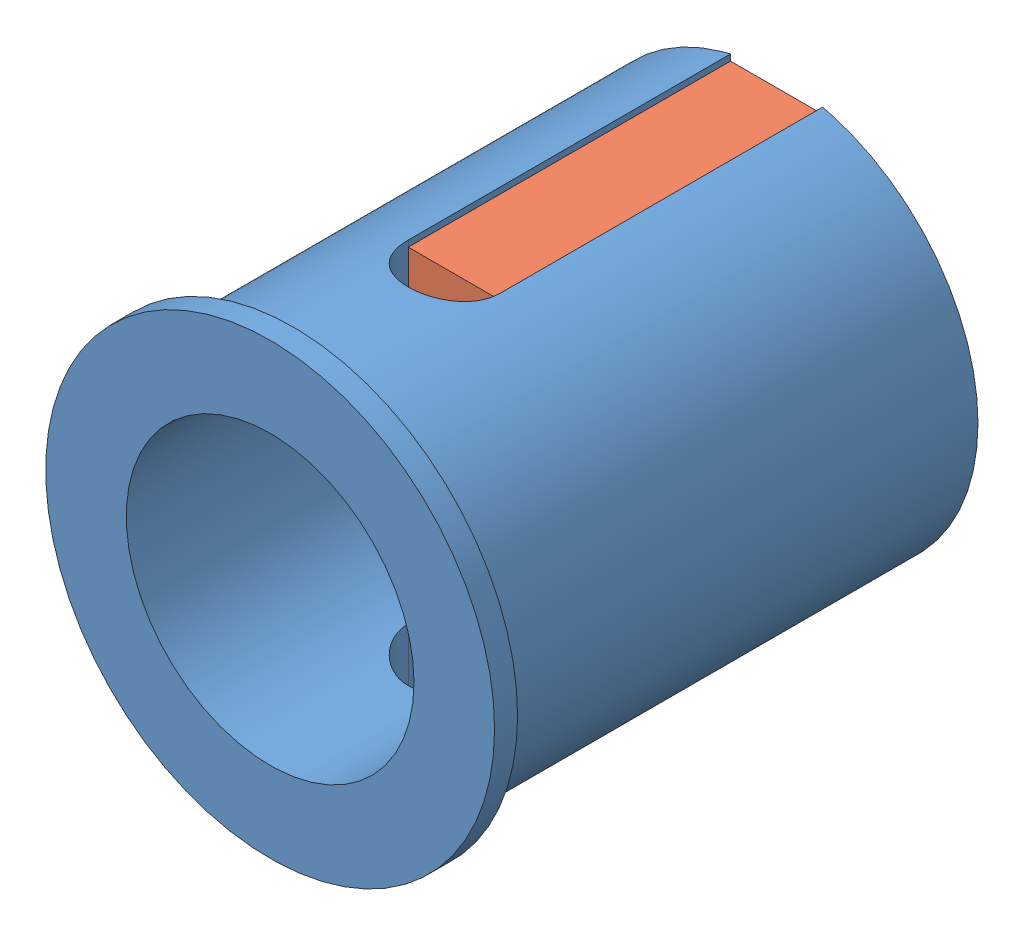
SolidWorks assembly ТП.002.08.01.02.00 - Втулка шкива, configuration 00. Lengths in mm.
Overall size (39 39 44).
2 component instances, 2 part files, 4 mates.
Components (placement in the parent):
- ТП.002.08.01.02.01 - Втулка шкива приводного-1: ТП.002.08.01.02.01 - Втулка шкива приводного [--] at origin size (39 39 44)
- ТП.002.08.01.02.02 - Шпонка 8х8х28-1: ТП.002.08.01.02.02 - Шпонка 8х8х28 [--] at (0 0 -42) x (-1 0 0) z (0 0 -1) size (8 8 28)
Mates (geometry in assembly coordinates):
- На месте1: in place: plane of ТП.002.08.01.02.01 - Втулка шкива приводного-1 through (0 0 -42) normal (0 0 -1); plane of ТП.002.08.01.02.02 - Шпонка 8х8х28-1 through (0 0 -42) normal (0 0 -1); moOrthogonalPlaneRef_w of ТП.002.08.01.02.01 - Втулка шкива приводного-1 through (0 0 -42) normal (0 0 -1); plane of ТП.002.08.01.02.02 - Шпонка 8х8х28-1 through (0 0 -42) normal (0 1 0); plane of ТП.002.08.01.02.01 - Втулка шкива приводного-1 through (0 0 -42) normal (0 0 -1); plane of ТП.002.08.01.02.02 - Шпонка 8х8х28-1 through (0 0 -42) normal (-1 0 0); plane of ТП.002.08.01.02.01 - Втулка шкива приводного-1 through (0 0 -42) normal (0 0 -1); unknown of ТП.002.08.01.02.02 - Шпонка 8х8х28-1
- Совпадение1: coincident: plane of ТП.002.08.01.02.01 - Втулка шкива приводного-1; plane of ТП.002.08.01.02.02 - Шпонка 8х8х28-1
- Совпадение2: coincident: moOrthogonalPlaneRef_w of ТП.002.08.01.02.01 - Втулка шкива приводного-1 through (0 0 -42) normal (0 1 0); plane of ТП.002.08.01.02.02 - Шпонка 8х8х28-1 through (0 0 -42) normal (0 1 0)
- Совпадение3: coincident: moOrthogonalPlaneRef_w of ТП.002.08.01.02.01 - Втулка шкива приводного-1 through (0 0 -42) normal (1 0 0); plane of ТП.002.08.01.02.02 - Шпонка 8х8х28-1 through (0 0 -42) normal (-1 0 0)
